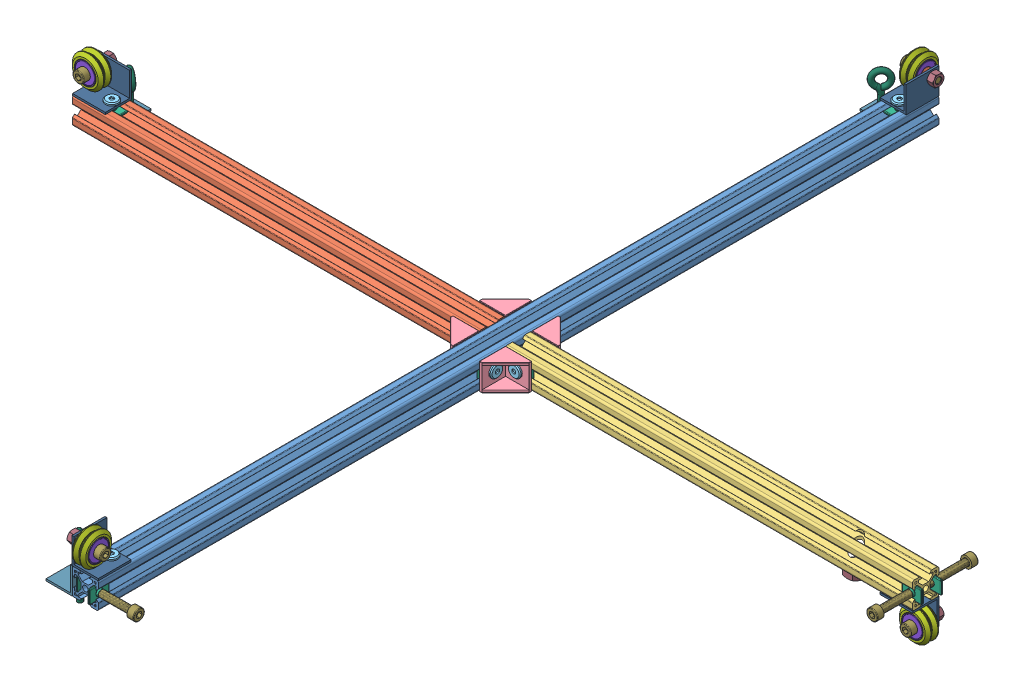
SolidWorks assembly BoxQR-rigidZstage, configuration Standard. Lengths in mm.
Overall size (653.89 73.89 664.44).
117 component instances, 15 part files, 46 mates.
Components (placement in the parent):
- V-Slot-20x20x640-1: V-Slot-20x20x640 [Default] at origin size (20 20 640)
- V-Slot-20x20x310-3: V-Slot-20x20x310 [Default] at (-10 0 -320) x (0 0 -1) z (1 0 0) size (20 20 310)
- V-Slot-20x20x310+hole-2: V-Slot-20x20x310+hole [Default] at (320 0 -320) x (0 0 -1) z (1 0 0) size (20 20 310)
- stageCorner-1: stageCorner [Standard] at (10 0 -310) x (1 0 0) z (0 -1 0) size (26.35 26.35 20)
  - Cast - 90 Degree Corner Bracket-1: Cast - 90 Degree Corner Bracket [Default] at origin size (20.75 20.75 20)
  - 5mm x 8mm Bolt with Tee Nut-1: 5mm x 8mm Bolt with Tee Nut [Default] at (-31.0938 20.4769 7.7195) x (-1 0 0) z (0 -1 0) size (10.1 10 15)
    - 5mm x 8mm Low Profile Socket Head Screw-1: 5mm x 8mm Low Profile Socket Head Screw [5mm x 8mm Low Profile] at (-34.8438 7.7195 10.4769) size (10.1 9.5 9.5)
    - Tee nut-1: Tee nut [Default] at (-28.2938 2.7205 17.9769) x (0 0 -1) z (1 0 0) size (15 10 3.3)
  - 5mm x 8mm Bolt with Tee Nut-2: 5mm x 8mm Bolt with Tee Nut [Default] at (-0.4769 -31.0938 7.7195) x (0 -1 0) z (1 0 0) size (10.1 10 15)
    - 5mm x 8mm Low Profile Socket Head Screw-1: 5mm x 8mm Low Profile Socket Head Screw [5mm x 8mm Low Profile] at (-34.8438 7.7195 10.4769) size (10.1 9.5 9.5)
    - Tee nut-1: Tee nut [Default] at (-28.2938 2.7205 17.9769) x (0 0 -1) z (1 0 0) size (15 10 3.3)
- stageCorner+Wheel-1: stageCorner+Wheel [Standard] at (0 25 -5) x (0 0 1) z (-1 0 0) size (34.45 33.8 25.38)
  - Derlin-V-Wheel+Bearings-1: Derlin-V-Wheel+Bearings [Standard] at origin size (23.89 23.89 11)
    - Delrin Dual V-Wheel-1: Delrin Dual V-Wheel [Default] at origin size (23.89 23.89 10.23)
    - Precision Ball Bearing-1: Precision Ball Bearing [Default] at (0 0 3) x (0 0 -1) z (1 0 0) size (5 16 16)
    - Precision Ball Bearing-2: Precision Ball Bearing [Default] at (0 0 -3) x (0 0 -1) z (1 0 0) size (5 16 16)
    - 5mm Precision Washer-1: 5mm Precision Washer [Default] at (0 0 -0.5) x (0 0 1) z (-1 0 0) size (1 10 10)
  - stageWheelAngle-1: stageWheelAngle [Standard] at (-20 -15 10.175) x (0 0 -1) z (1 0 0) size (20 20 25)
  - .125 Inch Aluminum Spacer-1: .125 Inch Aluminum Spacer [Default] at (0 0 8.675) x (0 0 -1) z (1 0 0) size (3.17 8 8)
  - socket head cap screw_din_a2-1: socket head cap screw_din_a2 [DIN 912 M5 x 20 --- 20C] at (0 0 -10.5) x (0 0 1) z (-1 0 0) size (25 8.5 8.5)
  - hex nut style 1 gradeab_din_a2-1: hex nut style 1 gradeab_din_a2 [Hexagon Nut ISO 4032 - M5 - D - C] at (0 0 10.175) x (-0.906893 -0.42136 0) z (0 0 -1) size (8 9.24 4.7)
  - 5mm x 8mm Bolt with Tee Nut-1: 5mm x 8mm Bolt with Tee Nut [Default] at (-25.4769 -46.5938 7.8945) x (0 -1 0) z (1 0 0) size (10.1 10 15)
    - 5mm x 8mm Low Profile Socket Head Screw-1: 5mm x 8mm Low Profile Socket Head Screw [5mm x 8mm Low Profile] at (-34.8438 7.7195 10.4769) size (10.1 9.5 9.5)
    - Tee nut-1: Tee nut [Default] at (-28.2938 2.7205 17.9769) x (0 0 -1) z (1 0 0) size (15 10 3.3)
- stageCorner-2: stageCorner [Standard] at (-10 0 -310) x (0 0 1) z (0 -1 0) size (26.35 26.35 20)
  - Cast - 90 Degree Corner Bracket-1: Cast - 90 Degree Corner Bracket [Default] at origin size (20.75 20.75 20)
  - 5mm x 8mm Bolt with Tee Nut-1: 5mm x 8mm Bolt with Tee Nut [Default] at (-31.0938 20.4769 7.7195) x (-1 0 0) z (0 -1 0) size (10.1 10 15)
    - 5mm x 8mm Low Profile Socket Head Screw-1: 5mm x 8mm Low Profile Socket Head Screw [5mm x 8mm Low Profile] at (-34.8438 7.7195 10.4769) size (10.1 9.5 9.5)
    - Tee nut-1: Tee nut [Default] at (-28.2938 2.7205 17.9769) x (0 0 -1) z (1 0 0) size (15 10 3.3)
  - 5mm x 8mm Bolt with Tee Nut-2: 5mm x 8mm Bolt with Tee Nut [Default] at (-0.4769 -31.0938 7.7195) x (0 -1 0) z (1 0 0) size (10.1 10 15)
    - 5mm x 8mm Low Profile Socket Head Screw-1: 5mm x 8mm Low Profile Socket Head Screw [5mm x 8mm Low Profile] at (-34.8438 7.7195 10.4769) size (10.1 9.5 9.5)
    - Tee nut-1: Tee nut [Default] at (-28.2938 2.7205 17.9769) x (0 0 -1) z (1 0 0) size (15 10 3.3)
- stageCorner-3: stageCorner [Standard] at (-10 0 -330) x (-1 0 0) z (0 -1 0) size (26.35 26.35 20)
  - Cast - 90 Degree Corner Bracket-1: Cast - 90 Degree Corner Bracket [Default] at origin size (20.75 20.75 20)
  - 5mm x 8mm Bolt with Tee Nut-1: 5mm x 8mm Bolt with Tee Nut [Default] at (-31.0938 20.4769 7.7195) x (-1 0 0) z (0 -1 0) size (10.1 10 15)
    - 5mm x 8mm Low Profile Socket Head Screw-1: 5mm x 8mm Low Profile Socket Head Screw [5mm x 8mm Low Profile] at (-34.8438 7.7195 10.4769) size (10.1 9.5 9.5)
    - Tee nut-1: Tee nut [Default] at (-28.2938 2.7205 17.9769) x (0 0 -1) z (1 0 0) size (15 10 3.3)
  - 5mm x 8mm Bolt with Tee Nut-2: 5mm x 8mm Bolt with Tee Nut [Default] at (-0.4769 -31.0938 7.7195) x (0 -1 0) z (1 0 0) size (10.1 10 15)
    - 5mm x 8mm Low Profile Socket Head Screw-1: 5mm x 8mm Low Profile Socket Head Screw [5mm x 8mm Low Profile] at (-34.8438 7.7195 10.4769) size (10.1 9.5 9.5)
    - Tee nut-1: Tee nut [Default] at (-28.2938 2.7205 17.9769) x (0 0 -1) z (1 0 0) size (15 10 3.3)
- stageAdjustingAngle-1: stageAdjustingAngle [Standard] at (-10 -10 0) x (-1 0 0) z (0 0 -1) size (26.85 20 20.5)
  - stageAdjustingAngle-1: stageAdjustingAngle [Standard] at origin size (20 20 20)
  - 5mm x 8mm Bolt with Tee Nut-1: 5mm x 8mm Bolt with Tee Nut [Default] at (-31.5938 2.2805 17.4769) x (-1 0 0) z (0 0 -1) size (10.1 10 15)
    - 5mm x 8mm Low Profile Socket Head Screw-1: 5mm x 8mm Low Profile Socket Head Screw [5mm x 8mm Low Profile] at (-34.8438 7.7195 10.4769) size (10.1 9.5 9.5)
    - Tee nut-1: Tee nut [Default] at (-28.2938 2.7205 17.9769) x (0 0 -1) z (1 0 0) size (15 10 3.3)
- stageCorner+Wheel-5: stageCorner+Wheel [Standard] at (315 -25 -320) x (1 0 0) z (0 0 -1) size (34.45 33.8 25.38)
  - Derlin-V-Wheel+Bearings-1: Derlin-V-Wheel+Bearings [Standard] at origin size (23.89 23.89 11)
    - Delrin Dual V-Wheel-1: Delrin Dual V-Wheel [Default] at origin size (23.89 23.89 10.23)
    - Precision Ball Bearing-1: Precision Ball Bearing [Default] at (0 0 3) x (0 0 -1) z (1 0 0) size (5 16 16)
    - Precision Ball Bearing-2: Precision Ball Bearing [Default] at (0 0 -3) x (0 0 -1) z (1 0 0) size (5 16 16)
    - 5mm Precision Washer-1: 5mm Precision Washer [Default] at (0 0 -0.5) x (0 0 1) z (-1 0 0) size (1 10 10)
  - stageWheelAngle-1: stageWheelAngle [Standard] at (-20 -15 10.175) x (0 0 -1) z (1 0 0) size (20 20 25)
  - .125 Inch Aluminum Spacer-1: .125 Inch Aluminum Spacer [Default] at (0 0 8.675) x (0 0 -1) z (1 0 0) size (3.17 8 8)
  - socket head cap screw_din_a2-1: socket head cap screw_din_a2 [DIN 912 M5 x 20 --- 20C] at (0 0 -10.5) x (0 0 1) z (-1 0 0) size (25 8.5 8.5)
  - hex nut style 1 gradeab_din_a2-1: hex nut style 1 gradeab_din_a2 [Hexagon Nut ISO 4032 - M5 - D - C] at (0 0 10.175) x (-0.906893 -0.42136 0) z (0 0 -1) size (8 9.24 4.7)
  - 5mm x 8mm Bolt with Tee Nut-1: 5mm x 8mm Bolt with Tee Nut [Default] at (-25.4769 -46.5938 7.8945) x (0 -1 0) z (1 0 0) size (10.1 10 15)
    - 5mm x 8mm Low Profile Socket Head Screw-1: 5mm x 8mm Low Profile Socket Head Screw [5mm x 8mm Low Profile] at (-34.8438 7.7195 10.4769) size (10.1 9.5 9.5)
    - Tee nut-1: Tee nut [Default] at (-28.2938 2.7205 17.9769) x (0 0 -1) z (1 0 0) size (15 10 3.3)
- stageAdjustingAngle-2: stageAdjustingAngle [Standard] at (-320 -10 -330) x (0 0 -1) z (1 0 0) size (26.85 20 20.5)
  - stageAdjustingAngle-1: stageAdjustingAngle [Standard] at origin size (20 20 20)
  - 5mm x 8mm Bolt with Tee Nut-1: 5mm x 8mm Bolt with Tee Nut [Default] at (-31.5938 2.2805 17.4769) x (-1 0 0) z (0 0 -1) size (10.1 10 15)
    - 5mm x 8mm Low Profile Socket Head Screw-1: 5mm x 8mm Low Profile Socket Head Screw [5mm x 8mm Low Profile] at (-34.8438 7.7195 10.4769) size (10.1 9.5 9.5)
    - Tee nut-1: Tee nut [Default] at (-28.2938 2.7205 17.9769) x (0 0 -1) z (1 0 0) size (15 10 3.3)
- stageCorner-4: stageCorner [Standard] at (10 0 -330) x (0 0 -1) z (0 -1 0) size (26.35 26.35 20)
  - Cast - 90 Degree Corner Bracket-1: Cast - 90 Degree Corner Bracket [Default] at origin size (20.75 20.75 20)
  - 5mm x 8mm Bolt with Tee Nut-1: 5mm x 8mm Bolt with Tee Nut [Default] at (-31.0938 20.4769 7.7195) x (-1 0 0) z (0 -1 0) size (10.1 10 15)
    - 5mm x 8mm Low Profile Socket Head Screw-1: 5mm x 8mm Low Profile Socket Head Screw [5mm x 8mm Low Profile] at (-34.8438 7.7195 10.4769) size (10.1 9.5 9.5)
    - Tee nut-1: Tee nut [Default] at (-28.2938 2.7205 17.9769) x (0 0 -1) z (1 0 0) size (15 10 3.3)
  - 5mm x 8mm Bolt with Tee Nut-2: 5mm x 8mm Bolt with Tee Nut [Default] at (-0.4769 -31.0938 7.7195) x (0 -1 0) z (1 0 0) size (10.1 10 15)
    - 5mm x 8mm Low Profile Socket Head Screw-1: 5mm x 8mm Low Profile Socket Head Screw [5mm x 8mm Low Profile] at (-34.8438 7.7195 10.4769) size (10.1 9.5 9.5)
    - Tee nut-1: Tee nut [Default] at (-28.2938 2.7205 17.9769) x (0 0 -1) z (1 0 0) size (15 10 3.3)
- stageCorner+Wheel-8: stageCorner+Wheel [Standard] at (-315 25 -320) x (-1 0 0) z (0 0 -1) size (34.45 33.8 25.38)
  - Derlin-V-Wheel+Bearings-1: Derlin-V-Wheel+Bearings [Standard] at origin size (23.89 23.89 11)
    - Delrin Dual V-Wheel-1: Delrin Dual V-Wheel [Default] at origin size (23.89 23.89 10.23)
    - Precision Ball Bearing-1: Precision Ball Bearing [Default] at (0 0 3) x (0 0 -1) z (1 0 0) size (5 16 16)
    - Precision Ball Bearing-2: Precision Ball Bearing [Default] at (0 0 -3) x (0 0 -1) z (1 0 0) size (5 16 16)
    - 5mm Precision Washer-1: 5mm Precision Washer [Default] at (0 0 -0.5) x (0 0 1) z (-1 0 0) size (1 10 10)
  - stageWheelAngle-1: stageWheelAngle [Standard] at (-20 -15 10.175) x (0 0 -1) z (1 0 0) size (20 20 25)
  - .125 Inch Aluminum Spacer-1: .125 Inch Aluminum Spacer [Default] at (0 0 8.675) x (0 0 -1) z (1 0 0) size (3.17 8 8)
  - socket head cap screw_din_a2-1: socket head cap screw_din_a2 [DIN 912 M5 x 20 --- 20C] at (0 0 -10.5) x (0 0 1) z (-1 0 0) size (25 8.5 8.5)
  - hex nut style 1 gradeab_din_a2-1: hex nut style 1 gradeab_din_a2 [Hexagon Nut ISO 4032 - M5 - D - C] at (0 0 10.175) x (-0.906893 -0.42136 0) z (0 0 -1) size (8 9.24 4.7)
  - 5mm x 8mm Bolt with Tee Nut-1: 5mm x 8mm Bolt with Tee Nut [Default] at (-25.4769 -46.5938 7.8945) x (0 -1 0) z (1 0 0) size (10.1 10 15)
    - 5mm x 8mm Low Profile Socket Head Screw-1: 5mm x 8mm Low Profile Socket Head Screw [5mm x 8mm Low Profile] at (-34.8438 7.7195 10.4769) size (10.1 9.5 9.5)
    - Tee nut-1: Tee nut [Default] at (-28.2938 2.7205 17.9769) x (0 0 -1) z (1 0 0) size (15 10 3.3)
- stageCorner+Wheel-9: stageCorner+Wheel [Standard] at (0 25 -635) x (0 0 -1) z (1 0 0) size (34.45 33.8 25.38)
  - Derlin-V-Wheel+Bearings-1: Derlin-V-Wheel+Bearings [Standard] at origin size (23.89 23.89 11)
    - Delrin Dual V-Wheel-1: Delrin Dual V-Wheel [Default] at origin size (23.89 23.89 10.23)
    - Precision Ball Bearing-1: Precision Ball Bearing [Default] at (0 0 3) x (0 0 -1) z (1 0 0) size (5 16 16)
    - Precision Ball Bearing-2: Precision Ball Bearing [Default] at (0 0 -3) x (0 0 -1) z (1 0 0) size (5 16 16)
    - 5mm Precision Washer-1: 5mm Precision Washer [Default] at (0 0 -0.5) x (0 0 1) z (-1 0 0) size (1 10 10)
  - stageWheelAngle-1: stageWheelAngle [Standard] at (-20 -15 10.175) x (0 0 -1) z (1 0 0) size (20 20 25)
  - .125 Inch Aluminum Spacer-1: .125 Inch Aluminum Spacer [Default] at (0 0 8.675) x (0 0 -1) z (1 0 0) size (3.17 8 8)
  - socket head cap screw_din_a2-1: socket head cap screw_din_a2 [DIN 912 M5 x 20 --- 20C] at (0 0 -10.5) x (0 0 1) z (-1 0 0) size (25 8.5 8.5)
  - hex nut style 1 gradeab_din_a2-1: hex nut style 1 gradeab_din_a2 [Hexagon Nut ISO 4032 - M5 - D - C] at (0 0 10.175) x (-0.906893 -0.42136 0) z (0 0 -1) size (8 9.24 4.7)
  - 5mm x 8mm Bolt with Tee Nut-1: 5mm x 8mm Bolt with Tee Nut [Default] at (-25.4769 -46.5938 7.8945) x (0 -1 0) z (1 0 0) size (10.1 10 15)
    - 5mm x 8mm Low Profile Socket Head Screw-1: 5mm x 8mm Low Profile Socket Head Screw [5mm x 8mm Low Profile] at (-34.8438 7.7195 10.4769) size (10.1 9.5 9.5)
    - Tee nut-1: Tee nut [Default] at (-28.2938 2.7205 17.9769) x (0 0 -1) z (1 0 0) size (15 10 3.3)
- hex nut style 1 gradeab_din_a2-1: hex nut style 1 gradeab_din_a2 [Hexagon Nut ISO 4032 - M8 - D - C] at (267.07 -16.8 -320) x (0.866025 0 -0.5) z (0 -1 0) size (13 15.01 6.8)
- EYE-BOLT+Nut-1: EYE-BOLT+Nut [Standard] at (-305 14.3263 -339) x (-0.837169 0 -0.546944) z (-0.546944 0 0.837169) size (15 47.03 10.08)
  - TURNED-EYE-BOLT-1: TURNED-EYE-BOLT [Standard] at origin size (15 47.03 4)
  - hex nut style 1 gradeab_din_a2-1: hex nut style 1 gradeab_din_a2 [Hexagon Nut ISO 4032 - M4 - D - C] at (0 27.5263 0) x (0.930689 0 0.365813) z (0 1 0) size (7 8.08 3.2)
- EYE-BOLT+Nut-2: EYE-BOLT+Nut [Standard] at (-19 14.3263 -15) x (-0.837169 0 -0.546944) z (-0.546944 0 0.837169) size (15 47.03 10.08)
  - TURNED-EYE-BOLT-1: TURNED-EYE-BOLT [Standard] at origin size (15 47.03 4)
  - hex nut style 1 gradeab_din_a2-1: hex nut style 1 gradeab_din_a2 [Hexagon Nut ISO 4032 - M4 - D - C] at (0 27.5263 0) x (0.930689 0 0.365813) z (0 1 0) size (7 8.08 3.2)
- stageAdjustingAngle-3: stageAdjustingAngle [Mirror] at (-10 -10 -640) x (-1 0 0) z (0 0 -1) size (20 20 37.5)
- EYE-BOLT+Nut-3: EYE-BOLT+Nut [Standard] at (-19 14.3263 -625) x (0.665739 0 -0.746185) z (-0.746185 0 -0.665739) size (15 47.03 10.08)
  - TURNED-EYE-BOLT-1: TURNED-EYE-BOLT [Standard] at origin size (15 47.03 4)
  - hex nut style 1 gradeab_din_a2-1: hex nut style 1 gradeab_din_a2 [Hexagon Nut ISO 4032 - M4 - D - C] at (0 27.5263 0) x (0.930689 0 0.365813) z (0 1 0) size (7 8.08 3.2)
- 5mm x 8mm Bolt with Tee Nut-1: 5mm x 8mm Bolt with Tee Nut [Default] at (21.5938 -7.7195 -643.4769) size (10.1 10 15)
  - 5mm x 8mm Low Profile Socket Head Screw-1: 5mm x 8mm Low Profile Socket Head Screw [5mm x 8mm Low Profile] at (-34.8438 7.7195 10.4769) size (10.1 9.5 9.5)
  - Tee nut-1: Tee nut [Default] at (-28.2938 2.7205 17.9769) x (0 0 -1) z (1 0 0) size (15 10 3.3)
- Tee nut-1: Tee nut [Default] at (325 -4.498 -311.8) x (-1 0 0) z (0 0 -1) size (15 10 3.3)
- Tee nut-2: Tee nut [Default] at (310 -5.5 -328.2) size (15 10 3.3)
- Tee nut-3: Tee nut [Default] at (8.2 -4.498 -10) x (0 0 1) z (-1 0 0) size (15 10 3.3)
- socket head cap screw_din_a2-1: socket head cap screw_din_a2 [DIN 912 M5 x 30 --- 22C] at (317.5 0.501 -281.6) x (0 0 -1) z (0.678222 0.734857 0) size (35 8.5 8.5)
- socket head cap screw_din_a2-2: socket head cap screw_din_a2 [DIN 912 M5 x 30 --- 22C] at (317.5 -0.501 -358.4) x (0 0 1) z (0.605921 0.795525 0) size (35 8.5 8.5)
- socket head cap screw_din_a2-3: socket head cap screw_din_a2 [DIN 912 M5 x 30 --- 22C] at (38.4 0.501 -2.5) x (-1 0 0) z (0 0.962364 -0.271763) size (35 8.5 8.5)
Mates (geometry in assembly coordinates):
- Coincident1: coincident anti-aligned: plane of V-Slot-20x20x640-1 through (0 0 -320) normal (0 0 1); plane of V-Slot-20x20x310-3 through (-10 0 -320) normal (0 0 -1)
- Coincident2: coincident anti-aligned: plane of V-Slot-20x20x640-1 through (-10 4.9072 -640) normal (-1 0 0); plane of V-Slot-20x20x310-3 through (-10 -4.9072 -310.79) normal (1 0 0)
- Coincident3: coincident aligned: plane of V-Slot-20x20x640-1 through (0 0 0) normal (0 1 0); plane of V-Slot-20x20x310-3
- Coincident4: coincident aligned: plane of V-Slot-20x20x640-1 through (0 0 0) normal (0 1 0); plane of V-Slot-20x20x310+hole-2
- Coincident5: coincident aligned: plane of V-Slot-20x20x310-3 through (-10 0 -320) normal (0 0 -1); plane of V-Slot-20x20x310+hole-2 through (320 0 -320) normal (0 0 -1)
- Coincident6: coincident anti-aligned: plane of V-Slot-20x20x640-1 through (10 4.9072 -640) normal (1 0 0); plane of V-Slot-20x20x310+hole-2 through (10 -4.9072 -310.79) normal (-1 0 0)
- Coincident7: coincident anti-aligned: plane of V-Slot-20x20x640-1 through (0 0 0) normal (0 1 0); plane of stageCorner-1/Cast - 90 Degree Corner Bracket-1 through (10 0 -310) normal (0 -1 0)
- Coincident8: coincident anti-aligned: plane of V-Slot-20x20x310+hole-2 through (10 -4.9072 -310) normal (0 0 1); plane of stageCorner-1/Cast - 90 Degree Corner Bracket-1 through (29.75 -10 -310) normal (0 0 -1)
- Coincident9: coincident anti-aligned: plane of V-Slot-20x20x640-1 through (10 -4.9072 -640) normal (1 0 0); plane of stageCorner-1/Cast - 90 Degree Corner Bracket-1 through (10 -10 -310) normal (-1 0 0)
- Coincident10: coincident anti-aligned: plane of V-Slot-20x20x640-1 through (0 0 0) normal (1 0 0); plane of stageCorner+Wheel-1/Derlin-V-Wheel+Bearings-1/Delrin Dual V-Wheel-1 through (0 25 -5) normal (-1 0 0)
- Coincident11: coincident anti-aligned: plane of V-Slot-20x20x640-1 through (4.9072 10 -640) normal (0 1 0); plane of stageCorner+Wheel-1/stageWheelAngle-1 through (-10.175 10 0) normal (0 -1 0)
- Coincident12: coincident aligned: plane of V-Slot-20x20x640-1 through (-9.21 -4.9072 0) normal (0 0 1); plane of stageCorner+Wheel-1/stageWheelAngle-1 through (-10.175 10 0) normal (0 0 1)
- Coincident13: coincident anti-aligned: plane of V-Slot-20x20x310+hole-2 through (10 -10 -315.0928) normal (0 -1 0); plane of stageCorner+Wheel-5/stageWheelAngle-1 through (320 -10 -330.175) normal (0 1 0)
- Coincident14: coincident aligned: plane of V-Slot-20x20x310+hole-2 through (320 0 -320) normal (0 0 -1); plane of stageCorner+Wheel-5/Derlin-V-Wheel+Bearings-1/Delrin Dual V-Wheel-1 through (315 -25 -320) normal (0 0 -1)
- Coincident15: coincident aligned: plane of V-Slot-20x20x310+hole-2 through (320 -4.9072 -310.79) normal (1 0 0); plane of stageCorner+Wheel-5/stageWheelAngle-1 through (320 -10 -330.175) normal (1 0 0)
- Coincident16: coincident anti-aligned: plane of V-Slot-20x20x640-1 through (-10 -4.9072 -640) normal (-1 0 0); plane of stageAdjustingAngle-1/stageAdjustingAngle-1 through (-10 -10 -20) normal (1 0 0)
- Coincident17: coincident aligned: plane of V-Slot-20x20x640-1 through (-4.9072 -10 -640) normal (0 -1 0); plane of stageAdjustingAngle-1/stageAdjustingAngle-1 through (-10 -10 -20) normal (0 -1 0)
- Coincident18: coincident aligned: plane of V-Slot-20x20x640-1 through (-9.21 -4.9072 0) normal (0 0 1); plane of stageAdjustingAngle-1/stageAdjustingAngle-1 through (-10 -10 0) normal (0 0 1)
- Concentric1: concentric anti-aligned: cylinder of V-Slot-20x20x310+hole-2 through (267.07 -10 -320) axis (0 1 0) radius 4.5; cylinder of hex nut style 1 gradeab_din_a2-1 through (267.07 -10 -320) axis (0 -1 0) radius 3.4
- Parallel1: parallel aligned: plane of V-Slot-20x20x310+hole-2 through (10 -4.9072 -330) normal (0 0 -1); plane of hex nut style 1 gradeab_din_a2-1 through (263.3172 -10 -326.5) normal (0 0 -1)
- Coincident19: coincident anti-aligned: plane of V-Slot-20x20x310+hole-2 through (10 -10 -324.9072) normal (0 -1 0); plane of hex nut style 1 gradeab_din_a2-1 through (270.8228 -10 -313.5) normal (0 1 0)
- Coincident27: coincident aligned: plane of V-Slot-20x20x640-1 through (-9.21 -4.9072 -640) normal (0 0 -1); plane of stageAdjustingAngle-3 through (-10 -10 -640) normal (0 0 -1)
- Coincident28: coincident anti-aligned: plane of V-Slot-20x20x640-1 through (-10 -4.9072 -640) normal (-1 0 0); plane of stageAdjustingAngle-3 through (-10 -10 -620) normal (1 0 0)
- Coincident29: coincident aligned: plane of V-Slot-20x20x640-1 through (-4.9072 -10 -640) normal (0 -1 0); plane of stageAdjustingAngle-3 through (-10 -10 -620) normal (0 -1 0)
- Concentric4: concentric aligned: cylinder of stageAdjustingAngle-3 through (-19 10 -625) axis (0 -1 0) radius 2.5; cylinder of EYE-BOLT+Nut-3/TURNED-EYE-BOLT-1 through (-19 4.8 -625) axis (0 -1 0) radius 2
- Concentric5: concentric aligned: cylinder of stageAdjustingAngle-2/stageAdjustingAngle-1 through (-305 10 -339) axis (0 -1 0) radius 2.5; cylinder of EYE-BOLT+Nut-1/TURNED-EYE-BOLT-1 through (-305 4.8 -339) axis (0 -1 0) radius 2
- Coincident31: coincident anti-aligned: plane of stageAdjustingAngle-2/stageAdjustingAngle-1 through (-300 -10 -330) normal (0 -1 0); plane of EYE-BOLT+Nut-1/hex nut style 1 gradeab_din_a2-1 through (-298.1454 -10 -337.5805) normal (0 1 0)
- Coincident32: coincident anti-aligned: plane of stageAdjustingAngle-3 through (-10 -10 -620) normal (0 -1 0); plane of EYE-BOLT+Nut-3/hex nut style 1 gradeab_din_a2-1 through (-21.4264 -10 -618.434) normal (0 1 0)
- Concentric6: concentric anti-aligned: cylinder of stageAdjustingAngle-3 through (-10 0 -633) axis (-1 0 0) radius 2.5; cylinder of 5mm x 8mm Bolt with Tee Nut-1/Tee nut-1 through (-8.35 0 -633) axis (1 0 0) radius 2.6
- Coincident33: coincident anti-aligned: plane of stageAdjustingAngle-3 through (-11.5 -10 -620) normal (-1 0 0); plane of 5mm x 8mm Bolt with Tee Nut-1/5mm x 8mm Low Profile Socket Head Screw-1 through (-11.5 2.5 -633) normal (1 0 0)
- Parallel2: parallel aligned: plane of V-Slot-20x20x640-1 through (-9.21 -4.9072 -640) normal (0 0 -1); plane of 5mm x 8mm Bolt with Tee Nut-1/Tee nut-1 through (-5.05 -4.999 -640.5) normal (0 0 -1)
- Coincident34: coincident anti-aligned: plane of V-Slot-20x20x310+hole-2 through (10 2.89 -311.8) normal (0 0 -1); plane of Tee nut-1 through (325 -4.498 -311.8) normal (0 0 1)
- Distance1: distance = 5 mm aligned: plane of V-Slot-20x20x310+hole-2 through (320 -4.9072 -310.79) normal (1 0 0); plane of Tee nut-1 through (325 -4.498 -313.45) normal (1 0 0)
- Coincident36: coincident anti-aligned: plane of V-Slot-20x20x310+hole-2 through (10 5.5 -313.4393) normal (0 -1 0); plane of Tee nut-1 through (325 5.5 -313.45) normal (0 1 0)
- Coincident37: coincident anti-aligned: plane of V-Slot-20x20x310+hole-2 through (10 2.89 -328.2) normal (0 0 1); plane of Tee nut-2 through (310 -5.5 -328.2) normal (0 0 -1)
- Coincident38: coincident anti-aligned: plane of V-Slot-20x20x310+hole-2 through (10 -5.5 -326.5607) normal (0 1 0); plane of Tee nut-2 through (310 -5.5 -326.55) normal (0 -1 0)
- Distance2: distance = 5 mm aligned: plane of V-Slot-20x20x640-1 through (-9.21 -4.9072 0) normal (0 0 1); plane of Tee nut-3 through (6.55 -4.498 5) normal (0 0 1)
- Coincident41: coincident anti-aligned: plane of V-Slot-20x20x640-1 through (8.2 2.89 -640) normal (-1 0 0); plane of Tee nut-3 through (8.2 -4.498 -10) normal (1 0 0)
- Coincident42: coincident anti-aligned: plane of V-Slot-20x20x640-1 through (6.5607 5.5 -640) normal (0 -1 0); plane of Tee nut-3 through (6.55 5.5 -10) normal (0 1 0)
- Concentric7: concentric anti-aligned: cylinder of Tee nut-1 through (317.5 0.501 -310.15) axis (0 0 -1) radius 2.4; cylinder of socket head cap screw_din_a2-1 through (317.5 0.501 -249.85) axis (0 0 1) radius 4.25
- Coincident44: coincident anti-aligned: plane of V-Slot-20x20x310+hole-2 through (10 -2.3393 -316.6) normal (0 0 1); plane of socket head cap screw_din_a2-1 through (315.9899 1.8947 -316.6) normal (0 0 -1)
- Concentric8: concentric anti-aligned: cylinder of Tee nut-2 through (317.5 -0.501 -329.85) axis (0 0 1) radius 2.4; cylinder of socket head cap screw_din_a2-2 through (317.5 -0.501 -390.15) axis (0 0 -1) radius 4.25
- Coincident45: coincident anti-aligned: plane of V-Slot-20x20x310+hole-2 through (10 -2.3393 -323.4) normal (0 0 -1); plane of socket head cap screw_din_a2-2 through (319.1348 -1.7462 -323.4) normal (0 0 1)
- Concentric9: concentric anti-aligned: cylinder of Tee nut-3 through (9.85 0.501 -2.5) axis (-1 0 0) radius 2.4; cylinder of socket head cap screw_din_a2-3 through (70.15 0.501 -2.5) axis (1 0 0) radius 4.25
- Coincident46: coincident anti-aligned: plane of V-Slot-20x20x640-1 through (3.4 -2.3393 -640) normal (1 0 0); plane of socket head cap screw_din_a2-3 through (3.4 1.0595 -0.5223) normal (-1 0 0)
- Coincident47: coincident aligned: plane of Tee nut-1 through (325 -4.498 -313.45) normal (1 0 0); plane of Tee nut-2 through (325 -5.5 -326.55) normal (1 0 0)
